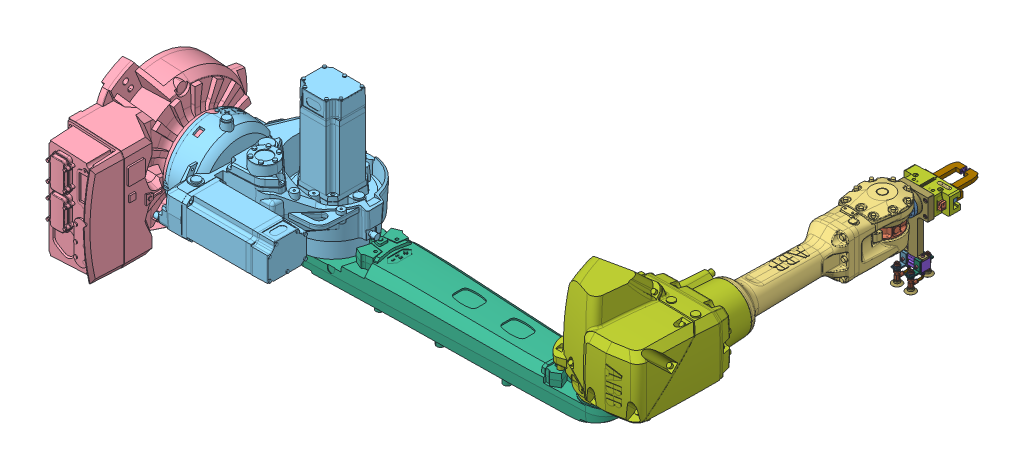
SolidWorks assembly assieme_gripper_2600, configuration Default. Lengths in mm.
Overall size (1582.11 860.05 1635.68).
81 component instances, 32 part files, 42 mates.
Components (placement in the parent):
- IRB2600_12kg-185_LINK6_CAD_rev02.step-3: IRB2600_12kg-185_LINK6_CAD_rev02.step [Default] at (-1460 0 1065) x (0 0 -1) z (1 0 0) size (34 63 63)
- IRB2600_12kg-185_LINK5_CAD_rev03.step-1: IRB2600_12kg-185_LINK5_CAD_rev03.step [Default] at (-1460 0 1065) x (0 0 -1) z (1 0 0) size (114.61 41 115.38)
- IRB2600_12kg-185_LINK4_CAD_rev04.step-1: IRB2600_12kg-185_LINK4_CAD_rev04.step [Default] at (-1460 0 1065) x (0 0 -1) z (1 0 0) size (583.5 285.91 153.38)
- IRB2600_12kg-185_BASE_CAD_rev02.step-1: IRB2600_12kg-185_BASE_CAD_rev02.step [Default] at (-1460 0 1065) x (0 0 -1) z (1 0 0) size (682.68 553.32 230.01)
- IRB2600_12kg-185_LINK1_CAD_rev02.step-1: IRB2600_12kg-185_LINK1_CAD_rev02.step [Default] at (-1460 0 1065) x (0 0 -1) z (1 0 0) size (507.13 430.78 454)
- IRB2600_12kg-185_LINK2_CAD_rev02.step-1: IRB2600_12kg-185_LINK2_CAD_rev02.step [Default] at (-1460 0 1065) x (0 0 -1) z (1 0 0) size (200 744.23 1070)
- IRB2600_12kg-185_LINK3_CAD_rev02.step-1: IRB2600_12kg-185_LINK3_CAD_rev02.step [Default] at (-1460 0 1065) x (0 0 -1) z (1 0 0) size (444.24 344.22 351.25)
- assieme_ventose-1: assieme_ventose [Default] at (367.5 -170.0409 9.326) x (0 -1 0) z (-1 0 0) size (78 109.5 91.15)
  - aluminiumm 30x30 670mm-1: aluminiumm 30x30 670mm [Default] at (-0.0409 0.674 335) size (30 30 71)
  - ecrou profil-1: ecrou profil [Default] at (-0.0409 9.834 352.85) x (-1 0 0) z (0 -1 0) size (15.9 15.7 7.3)
  - 189174_ESG-30-SF-HD-QS.stp-1: 189174_ESG-30-SF-HD-QS.stp [Default] at (48.9591 39.674 390) x (0 -1 0) z (0 0 -1) size (36.15 61.01 31.5)
    - 130519 ESHM-M14x1.stp-1: 130519 ESHM-M14x1.stp [Default] at (0 38 0) size (19.64 4.01 19.64)
    - 130519 ESHM-M14x1.stp-2: 130519 ESHM-M14x1.stp [Default] at (0 30 0) size (19.64 4.01 19.64)
    - 189239 ESH-HD-4-QS_part---(0).stp-1: 189239 ESH-HD-4-QS_part---(0).stp [Default] at origin size (28.4 50.01 16)
    - 189302 ESS-30-SF.stp-1: 189302 ESS-30-SF.stp [Default] at (0 -11 0) size (31.5 16 31.5)
  - socket head cap screw_iso-3: socket head cap screw_iso [ISO 4762 M5 x 12 - 12N] at (-0.0409 24.674 345) x (0 -1 0) z (-0.866025 0 0.5) size (17 8.5 8.5)
  - socket head cap screw_iso-4: socket head cap screw_iso [ISO 4762 M5 x 12 - 12N] at (-0.0409 24.674 390) x (0 -1 0) z (-0.866025 0 -0.5) size (17 8.5 8.5)
  - 189174_ESG-30-SF-HD-QS.stp-2: 189174_ESG-30-SF-HD-QS.stp [Default] at (48.9591 -38.326 367.5) x (0 1 0) z (0 0 1) size (36.15 61.01 31.5)
    - 130519 ESHM-M14x1.stp-1: 130519 ESHM-M14x1.stp [Default] at (0 38 0) size (19.64 4.01 19.64)
    - 130519 ESHM-M14x1.stp-2: 130519 ESHM-M14x1.stp [Default] at (0 30 0) size (19.64 4.01 19.64)
    - 189239 ESH-HD-4-QS_part---(0).stp-1: 189239 ESH-HD-4-QS_part---(0).stp [Default] at origin size (28.4 50.01 16)
    - 189302 ESS-30-SF.stp-1: 189302 ESS-30-SF.stp [Default] at (0 -11 0) size (31.5 16 31.5)
  - Parte12-1: Parte12 [Default] at (14.9591 39.674 390) x (0 -1 0) z (-1 0 0) size (38 20 36)
  - 189174_ESG-30-SF-HD-QS.stp-4: 189174_ESG-30-SF-HD-QS.stp [Default] at (48.9591 39.674 345) x (0 -1 0) z (0 0 -1) size (36.15 61.01 31.5)
    - 130519 ESHM-M14x1.stp-1: 130519 ESHM-M14x1.stp [Default] at (0 38 0) size (19.64 4.01 19.64)
    - 130519 ESHM-M14x1.stp-2: 130519 ESHM-M14x1.stp [Default] at (0 30 0) size (19.64 4.01 19.64)
    - 189239 ESH-HD-4-QS_part---(0).stp-1: 189239 ESH-HD-4-QS_part---(0).stp [Default] at origin size (28.4 50.01 16)
    - 189302 ESS-30-SF.stp-1: 189302 ESS-30-SF.stp [Default] at (0 -11 0) size (31.5 16 31.5)
  - Parte12_-1: Parte12_ [Default] at (14.9591 39.674 345) x (0 -1 0) z (-1 0 0) size (38 20 36)
  - Parte12_-2: Parte12_ [Default] at (14.9591 -38.326 367.5) x (0 1 0) z (-1 0 0) size (38 20 36)
  - ecrou profil_-1: ecrou profil_ [Default] at (-0.0409 9.834 382.15) x (1 0 0) z (0 -1 0) size (15.9 15.7 7.3)
  - ecrou profil_-2: ecrou profil_ [Default] at (-0.0409 -8.486 375.35) x (1 0 0) z (0 1 0) size (15.9 15.7 7.3)
  - socket head cap screw_iso-7: socket head cap screw_iso [ISO 4762 M5 x 12 - 12N] at (-0.0409 -23.326 367.5) x (0 1 0) z (0 0 -1) size (17 8.5 8.5)
  - 186108_QS-G1_4-6-I.stp-4: 186108_QS-G1_4-6-I.stp [Default] at (14.9591 0.6232 390) x (0 0 1) z (-1 0 0) size (17 17 20.2)
  - 186108_QS-G1_4-6-I.stp-5: 186108_QS-G1_4-6-I.stp [Default] at (14.9591 0.6232 367.5) x (0 0 1) z (-1 0 0) size (17 17 20.2)
  - 186108_QS-G1_4-6-I.stp-6: 186108_QS-G1_4-6-I.stp [Default] at (14.9591 0.6232 345) x (0 0 1) z (-1 0 0) size (17 17 20.2)
  - tubi_racc-1: tubi_racc [Default] at (14.9591 0.674 335) x (0 0 -1) z (1 0 0) size (51 64 28.5)
  - 186108_QS-G1_4-6-I.stp-7: 186108_QS-G1_4-6-I.stp [Default] at (-0.0409 0.674 405) x (-0.923728 -0.383049 0) z (0 0 -1) size (17 17 20.2)
- pinza_con_dita-1: pinza_con_dita [Default] at (-88.6356 -83.6124 -120.7912) size (151 60 163)
  - SCHUNK_1460275_JGP_P_125_1_000ohne-1: SCHUNK_1460275_JGP_P_125_1_000ohne [Default] at (88.6356 83.6124 120.7912) size (151 60 63)
    - SCHUNK_1460275_JGP_P_125_1_000ohne_3-1: SCHUNK_1460275_JGP_P_125_1_000ohne_3 [Default] at (-0.75 0 -39.1) x (0 1 0) z (-1 0 0) size (30 23.9 61.3)
    - SCHUNK_1460275_JGP_P_125_1_000ohne_3-2: SCHUNK_1460275_JGP_P_125_1_000ohne_3 [Default] at (0.75 0 -39.1) x (0 -1 0) z (1 0 0) size (30 23.9 61.3)
    - SCHUNK_1460275_JGP_P_125_1_000ohne_6-1: SCHUNK_1460275_JGP_P_125_1_000ohne_6 [Default] at (-53 0 -25.15) x (-1 0 0) z (0 1 0) size (12 16 20)
    - SCHUNK_1460275_JGP_P_125_1_000ohne_6-2: SCHUNK_1460275_JGP_P_125_1_000ohne_6 [Default] at (53 0 -9.15) x (1 0 0) z (0 1 0) size (12 16 20)
    - SCHUNK_1460275_JGP_P_125_1_000ohne_9-1: SCHUNK_1460275_JGP_P_125_1_000ohne_9 [Default] at (36.65 29.3 -47.65) x (1 0 0) z (0 1 0) size (43 11 0.3)
    - SCHUNK_1460275_JGP_P_125_1_000ohne_11-1: SCHUNK_1460275_JGP_P_125_1_000ohne_11 [Default] at (3 26.125 -16) size (3.8 2.96 5)
    - SCHUNK_1460275_JGP_P_125_1_000ohne_13-1: SCHUNK_1460275_JGP_P_125_1_000ohne_13 [Default] at (0 0 -5.5) x (-1 0 0) z (0 0 1) size (85.9 59.7 5.4)
    - SCHUNK_1460275_JGP_P_125_1_000ohne_15-1: SCHUNK_1460275_JGP_P_125_1_000ohne_15 [Default] at (0 0 -61) x (0 -1 0) z (0 0 -1) size (56.8 43.3 6.15)
    - SCHUNK_1460275_JGP_P_125_1_000ohne_17-1: SCHUNK_1460275_JGP_P_125_1_000ohne_17 [Default] x (1 0 0) z (0 1 0) size (151 62 60)
  - chela-1: chela [Default] at (169.8768 23.5753 87.8636) x (-1 0 0) z (0 0 -1) size (57.55 19.7 100.99)
    - gommino-1: gommino [Default] at (73.7442 50.1871 130.0724) x (0 0 -1) z (1 0 0) size (20 19.7 3)
    - chela_senza_gommino-1: chela_senza_gommino [Default] at (19.1912 50.1871 30.0724) size (54.55 19.7 100.99)
  - chela-3: chela [Default] at (7.3944 143.6495 87.8636) x (1 0 0) z (0 0 -1) size (57.55 19.7 100.99)
    - gommino-1: gommino [Default] at (73.7442 50.1871 130.0724) x (0 0 -1) z (1 0 0) size (20 19.7 3)
    - chela_senza_gommino-1: chela_senza_gommino [Default] at (19.1912 50.1871 30.0724) size (54.55 19.7 100.99)
  - socket countersunk head screw_iso-3: socket countersunk head screw_iso [ISO 10642 - M4 x 35 - 20N] at (143.1356 83.6124 37.0112) x (0 0 1) z (-0.999808 0.019592 0) size (35 7.53 7.53)
  - socket countersunk head screw_iso-5: socket countersunk head screw_iso [ISO 10642 - M4 x 35 - 20N] at (119.0725 83.6124 37.0112) x (0 0 1) z (-1 0 0) size (35 7.53 7.53)
  - countersunk flat head cross recess screw_iso-1: countersunk flat head cross recess screw_iso [ISO 7046-1 - M2 x 8 - Z - 8N] at (93.1325 83.6124 -27.2088) x (1 0 0) z (0 -0.924225 -0.381849) size (8 3.8 3.8)
  - countersunk flat head cross recess screw_iso-2: countersunk flat head cross recess screw_iso [ISO 7046-1 - M2 x 8 - Z - 8N] at (93.1325 83.6124 -37.2088) size (8 3.8 3.8)
  - socket countersunk head screw_iso-7: socket countersunk head screw_iso [ISO 10642 - M4 x 35 - 20N] at (34.1356 83.6124 37.0112) x (0 0 1) z (-0.999808 -0.019592 0) size (35 7.53 7.53)
  - countersunk flat head cross recess screw_iso-3: countersunk flat head cross recess screw_iso [ISO 7046-1 - M2 x 8 - Z - 8N] at (84.1387 83.6124 -27.2088) x (-1 0 0) z (0 0.924225 0.381849) size (8 3.8 3.8)
  - countersunk flat head cross recess screw_iso-4: countersunk flat head cross recess screw_iso [ISO 7046-1 - M2 x 8 - Z - 8N] at (84.1387 83.6124 -37.2088) x (-1 0 0) z (0 0 -1) size (8 3.8 3.8)
  - socket countersunk head screw_iso-8: socket countersunk head screw_iso [ISO 10642 - M4 x 35 - 20N] at (58.1987 83.6124 37.0112) x (0 0 1) z (-1 0 0) size (35 7.53 7.53)
- Parte10-1: Parte10 [Default] at origin
- flangia_2600-1: flangia_2600 [Default] at (-1460 0 35) x (-1 0 0) z (0 0 -1) size (100 199.14 36)
- socket head cap screw_iso-4: socket head cap screw_iso [ISO 4762 M5 x 35 - 22N] at (21.6506 12.5 5) x (0 0 1) z (0.5 -0.866025 0) size (40 8.5 8.5)
- socket head cap screw_iso-7: socket head cap screw_iso [ISO 4762 M5 x 35 - 22N] at (0 25 5) x (0 0 1) z (1 0 0) size (40 8.5 8.5)
- socket head cap screw_iso-8: socket head cap screw_iso [ISO 4762 M5 x 35 - 22N] at (-21.6506 12.5 5) x (0 0 1) z (0.5 0.866025 0) size (40 8.5 8.5)
- socket head cap screw_iso-9: socket head cap screw_iso [ISO 4762 M5 x 35 - 22N] at (-21.6506 -12.5 5) x (0 0 1) z (-0.5 0.866025 0) size (40 8.5 8.5)
- socket head cap screw_iso-10: socket head cap screw_iso [ISO 4762 M5 x 35 - 22N] at (0 -25 5) x (0 0 1) z (-1 0 0) size (40 8.5 8.5)
- socket head cap screw_iso-11: socket head cap screw_iso [ISO 4762 M5 x 35 - 22N] at (21.6506 -12.5 5) x (0 0 1) z (-0.5 -0.866025 0) size (40 8.5 8.5)
- socket head cap screw_iso-13: socket head cap screw_iso [ISO 4762 M6 x 25 - 25N] at (41 -22.5 18) x (0 0 -1) z (1 0 0) size (31 10 10)
- socket head cap screw_iso-14: socket head cap screw_iso [ISO 4762 M6 x 25 - 25N] at (41 22.5 18) x (0 0 -1) z (1 0 0) size (31 10 10)
- socket head cap screw_iso-15: socket head cap screw_iso [ISO 4762 M6 x 25 - 25N] at (-41 22.5 18) x (0 0 -1) z (1 0 0) size (31 10 10)
- socket head cap screw_iso-16: socket head cap screw_iso [ISO 4762 M6 x 25 - 25N] at (-41 -22.5 18) x (0 0 -1) z (1 0 0) size (31 10 10)
- ecrou profil_-1: ecrou profil_ [Default] at (30.7 -160.86 10) x (0 0 1) z (0 -1 0) size (15.9 15.7 7.3)
- ecrou profil_-2: ecrou profil_ [Default] at (-30.7 -160.86 10) x (0 0 -1) z (0 -1 0) size (15.9 15.7 7.3)
- socket head cap screw_iso-17: socket head cap screw_iso [ISO 4762 M5 x 12 - 12N] at (-22.85 -145 10) x (0 -1 0) z (0.5 0 0.866025) size (17 8.5 8.5)
- socket head cap screw_iso-18: socket head cap screw_iso [ISO 4762 M5 x 12 - 12N] at (22.85 -145 10) x (0 -1 0) z (-1 0 0) size (17 8.5 8.5)
- Parte1^assieme_gripper_2600-1: Parte1^assieme_gripper_2600 [Default] at origin size (56.93 176 6) (virtual)
- 186108_QS-G1_4-6-I.stp-1: 186108_QS-G1_4-6-I.stp [Default] at (-50 0 10) x (0 0 -1) z (1 0 0) size (17 17 20.2)
Mates (geometry in assembly coordinates):
- Coincidente7: coordinate: point of IRB2600_12kg-185_LINK5_CAD_rev03.step-1; point of IRB2600_12kg-185_LINK4_CAD_rev04.step-1
- Coincidente8: coordinate: point of IRB2600_12kg-185_LINK2_CAD_rev02.step-1; point of IRB2600_12kg-185_LINK3_CAD_rev02.step-1
- Coincidente9: coordinate: point of IRB2600_12kg-185_BASE_CAD_rev02.step-1; point of IRB2600_12kg-185_LINK1_CAD_rev02.step-1
- Coincidente10: coordinate: point of IRB2600_12kg-185_BASE_CAD_rev02.step-1; point of IRB2600_12kg-185_LINK2_CAD_rev02.step-1
- Coincidente11: coordinate: point of IRB2600_12kg-185_LINK4_CAD_rev04.step-1; point of IRB2600_12kg-185_BASE_CAD_rev02.step-1
- Coincidente12: coordinate: point of IRB2600_12kg-185_LINK6_CAD_rev02.step-3; point of IRB2600_12kg-185_BASE_CAD_rev02.step-1
- Concentrico1: concentric aligned: cylinder of pinza_con_dita-1/SCHUNK_1460275_JGP_P_125_1_000ohne-1/SCHUNK_1460275_JGP_P_125_1_000ohne_17-1 through (-41 22.5 0) axis (0 0 1) radius 3.4; cylinder of flangia_2600-1 through (-41 22.5 0) axis (0 0 1) radius 3.4
- Coincidente16: coincident anti-aligned: plane of pinza_con_dita-1/SCHUNK_1460275_JGP_P_125_1_000ohne-1/SCHUNK_1460275_JGP_P_125_1_000ohne_17-1 through (0 0 0) normal (0 0 1); plane of flangia_2600-1 through (-1460 0 0) normal (0 0 -1)
- Coincidente17: coincident aligned: plane of pinza_con_dita-1/SCHUNK_1460275_JGP_P_125_1_000ohne-1/SCHUNK_1460275_JGP_P_125_1_000ohne_17-1 through (-50 30 0) normal (-1 0 0); plane of flangia_2600-1 through (-50 35 0) normal (-1 0 0)
- Coincidente18: coincident anti-aligned: plane of flangia_2600-1 through (21.6506 12.5 10) normal (0 0 -1); plane of socket head cap screw_iso-4 through (17.97 10.375 10) normal (0 0 1)
- Parallelo3: parallel aligned: plane of flangia_2600-1 through (50 35 0) normal (1 0 0); plane of socket head cap screw_iso-4 through (19.6086 11.3211 7.5) normal (1 0 0)
- Concentrico5: concentric aligned: cylinder of flangia_2600-1 through (41 -22.5 0) axis (0 0 1) radius 3.4; cylinder of socket head cap screw_iso-13 through (41 -22.5 49.75) axis (0 0 1) radius 5
- Coincidente20: coincident anti-aligned: plane of flangia_2600-1 through (41 -22.5 12) normal (0 0 1); plane of socket head cap screw_iso-13 through (41 -17.5 12) normal (0 0 -1)
- Concentrico6: concentric aligned: cylinder of flangia_2600-1 through (41 22.5 12) axis (0 0 1) radius 6; cylinder of socket head cap screw_iso-14 through (41 22.5 49.75) axis (0 0 1) radius 5
- Coincidente21: coincident anti-aligned: plane of flangia_2600-1 through (41 22.5 12) normal (0 0 1); plane of socket head cap screw_iso-14 through (41 27.5 12) normal (0 0 -1)
- Concentrico71: concentric aligned: cylinder of flangia_2600-1 through (-41 22.5 12) axis (0 0 1) radius 6; cylinder of socket head cap screw_iso-15 through (-41 22.5 49.75) axis (0 0 1) radius 5
- Coincidente221: coincident anti-aligned: plane of flangia_2600-1 through (-41 22.5 12) normal (0 0 1); plane of socket head cap screw_iso-15 through (-41 27.5 12) normal (0 0 -1)
- Concentrico8: concentric aligned: cylinder of flangia_2600-1 through (-41 -22.5 0) axis (0 0 1) radius 3.4; cylinder of socket head cap screw_iso-16 through (-41 -22.5 49.75) axis (0 0 1) radius 5
- Coincidente23: coincident anti-aligned: plane of flangia_2600-1 through (-41 -22.5 12) normal (0 0 1); plane of socket head cap screw_iso-16 through (-41 -17.5 12) normal (0 0 -1)
- Parallelo4: parallel anti-aligned: plane of flangia_2600-1 through (50 -35 0) normal (0 -1 0); plane of vassoioX1_componibile-1 through (302.4303 -434.8296 1005.4861) normal (0 1 0)
- Parallelo6: parallel aligned: plane of flangia_2600-1 through (-50 35 0) normal (-1 0 0); plane of assiene_distributore_valvola-1/7849_FR-4-1_4-C.stp-1/7849 FR-4-1_4-C - P1.stp-1 through (290.2496 -357.8805 979.0236) normal (0 0 -1)
- Parallelo7: parallel aligned: plane of flangia_2600-1 through (50 35 0) normal (0 1 0); plane of assiene_distributore_valvola-1/7849_FR-4-1_4-C.stp-1/7849 FR-4-1_4-C - P1.stp-1 through (290.2496 -268.8805 1009.0236) normal (0 1 0)
- Coincidente29: coordinate: unknown of pinza_con_dita-1/SCHUNK_1460275_JGP_P_125_1_000ohne-1
- Concentrico72: concentric aligned: cylinder of flangia_2600-1 through (21.6506 12.5 10) axis (0 0 -1) radius 5; cylinder of socket head cap screw_iso-4 through (21.6506 12.5 -26.75) axis (0 0 -1) radius 2.5
- Coincidente222: coincident anti-aligned: plane of assieme_ventose-1/aluminiumm 30x30 670mm-1 through (-32.5 -155 -5) normal (0 1 0); plane of flangia_2600-1 through (5.76 -155 143.6932) normal (0 -1 0)
- Coincidente223: coincident aligned: plane of assieme_ventose-1/aluminiumm 30x30 670mm-1 through (32.5 -170 10) normal (0 0 1); plane of flangia_2600-1 through (-1460 0 10) normal (0 0 1)
- Coincidente224: coincident anti-aligned: plane of assieme_ventose-1/189174_ESG-30-SF-HD-QS.stp-2/189239 ESH-HD-4-QS_part---(0).stp-1 through (0 -219 -29) normal (-1 0 0); plane of pinza_con_dita-1/SCHUNK_1460275_JGP_P_125_1_000ohne-1/SCHUNK_1460275_JGP_P_125_1_000ohne_17-1 through (0 0 0) normal (1 0 0)
- Coincidente225: coincident anti-aligned: plane of flangia_2600-1 through (15 -35 143.6932) normal (1 0 0); plane of ecrou profil_-1 through (15 -160.86 10) normal (-1 0 0)
- Coincidente226: coincident aligned: plane of flangia_2600-1 through (-33.9514 -156.76 14.3) normal (0 1 0); plane of ecrou profil_-1 through (15 -156.76 17.95) normal (0 1 0)
- Coincidente227: coincident aligned: plane of flangia_2600-1 through (-1460 0 10) normal (0 0 1); plane of ecrou profil_-1 through (30.7 -160.86 10) normal (0 0 1)
- Coincidente228: coincident aligned: plane of ecrou profil_-1 through (15 -155.06 6) normal (0 1 0); plane of ecrou profil_-2 through (-15 -155.06 14) normal (0 1 0)
- Coincidente229: coincident anti-aligned: plane of flangia_2600-1 through (-15 -35 143.6932) normal (-1 0 0); plane of ecrou profil_-2 through (-15 -160.86 10) normal (1 0 0)
- Coincidente230: coincident aligned: plane of ecrou profil_-1 through (15 -156.76 6) normal (0 0 -1); plane of ecrou profil_-2 through (-15 -156.76 6) normal (0 0 -1)
- Concentrico73: concentric anti-aligned: cylinder of flangia_2600-1 through (-22.85 35.001 10) axis (0 -1 0) radius 2.5; cylinder of socket head cap screw_iso-17 through (-22.85 -113.25 10) axis (0 1 0) radius 4.25
- Coincidente231: coincident anti-aligned: plane of flangia_2600-1 through (32.5 -150 0) normal (0 1 0); plane of socket head cap screw_iso-17 through (-19.1694 -150 7.875) normal (0 -1 0)
- Concentrico74: concentric anti-aligned: cylinder of flangia_2600-1 through (22.85 35.001 10) axis (0 -1 0) radius 2.5; cylinder of socket head cap screw_iso-18 through (22.85 -113.25 10) axis (0 1 0) radius 4.25
- Coincidente232: coincident anti-aligned: plane of flangia_2600-1 through (32.5 -150 0) normal (0 1 0); plane of socket head cap screw_iso-18 through (22.85 -150 14.25) normal (0 -1 0)
- Parallelo8: parallel aligned: plane of flangia_2600-1 through (15 -35 143.6932) normal (1 0 0); plane of socket head cap screw_iso-18 through (20.808 -147.5 8.8211) normal (1 0 0)
- Parallelo9: parallel aligned: plane of flangia_2600-1 through (-15 -35 143.6932) normal (-1 0 0); plane of socket head cap screw_iso-17 through (-20.808 -147.5 8.8211) normal (-1 0 0)
- Coincidente235: coincident anti-aligned: plane of flangia_2600-1 through (-50 35 0) normal (-1 0 0); plane of 186108_QS-G1_4-6-I.stp-1 through (-50 6.5785 10) normal (1 0 0)
- Coincidente236: coincident aligned: plane of pinza_con_dita-1/SCHUNK_1460275_JGP_P_125_1_000ohne-1/SCHUNK_1460275_JGP_P_125_1_000ohne_17-1 through (0 0 0) normal (0 1 0); plane of 186108_QS-G1_4-6-I.stp-1 through (-50 0 10) normal (0 1 0)
- Coincidente238: coincident anti-aligned: plane of flangia_2600-1 through (-1460 0 10) normal (0 0 1); plane of 186108_QS-G1_4-6-I.stp-1 through (-50 0 10) normal (0 0 -1)
